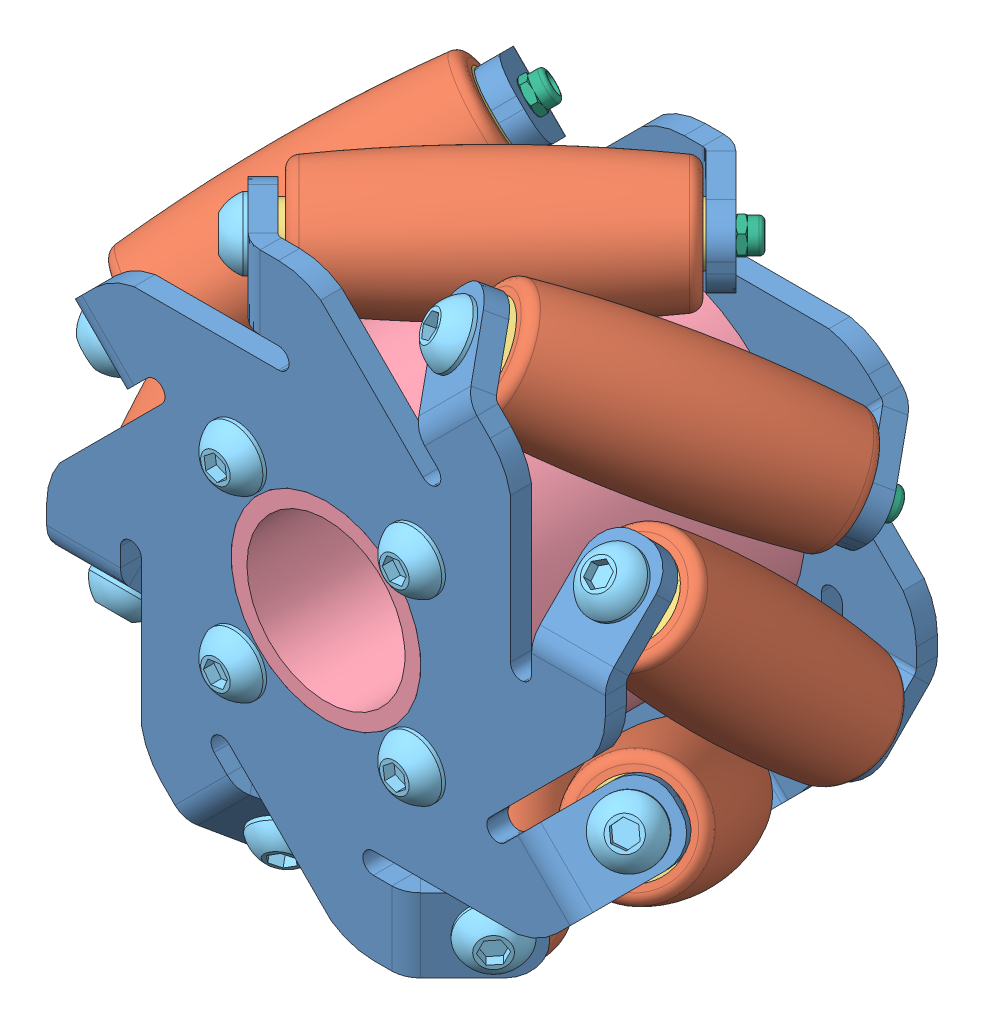
SolidWorks assembly MECANUM WHEEL, configuration Default. Lengths in mm.
Overall size (125.04 125.04 71.6).
51 component instances, 6 part files, 20 mates.
Components (placement in the parent):
- Frame-1: Frame [Default] at (12.3408 21.9505 61.841) x (0 1 0) z (0 0 -1) size (111.31 111.31 16.67)
- Roller-1: Roller [Default] at (12.3982 67.9505 33.7143) x (0.707107 0 -0.707107) z (0.372202 -0.850254 0.372202) size (56 24 24)
- Roller Bracket-1: Roller Bracket [Default] at (30.6779 67.9505 15.4346) x (-0.707107 0 -0.707107) z (0.707107 0 -0.707107) size (15 15 4)
- Shaft-1: Shaft [Default] at (12.3408 21.9505 20.3191) size (64 64 63)
- Frame-2: Frame [Default] at (12.3408 21.9505 6.2972) x (0 1 0) z (0 0 1) size (111.31 111.31 16.67)
- Roller Bracket-2: Roller Bracket [Default] at (-5.8815 67.9505 51.994) x (0.707107 0 0.707107) z (-0.707107 0 0.707107) size (15 15 4)
- Screw-1: Screw [Default] at (7.232 67.9505 38.8805) x (0.707107 0 -0.707107) z (0.582013 0.56791 0.582013) size (71.6 11.4 11.4)
- torque nut 08_iso-2: torque nut 08_iso [ISO 10511-M3-C] at (36.7139 67.9505 9.9933) x (-0.247306 -0.936845 -0.247306) z (0.707107 0 -0.707107) size (5.5 6.35 3.9)
- Roller Bracket-3: Roller Bracket [Default] at (57.834 41.5111 15.4346) x (-0.5 0.5 -0.707107) z (0.5 -0.5 -0.707107) size (15 15 4)
- Roller Bracket-4: Roller Bracket [Default] at (58.3408 3.6134 15.4346) x (0 0.707107 -0.707107) z (0 -0.707107 -0.707107) size (15 15 4)
- Roller Bracket-5: Roller Bracket [Default] at (31.9013 -23.5427 15.4346) x (0.5 0.5 -0.707107) z (-0.5 -0.5 -0.707107) size (15 15 4)
- Roller Bracket-6: Roller Bracket [Default] at (-5.9964 -24.0495 15.4346) x (0.707107 0 -0.707107) z (-0.707107 0 -0.707107) size (15 15 4)
- Roller Bracket-7: Roller Bracket [Default] at (-33.1525 2.3899 15.4346) x (0.5 -0.5 -0.707107) z (-0.5 0.5 -0.707107) size (15 15 4)
- Roller Bracket-8: Roller Bracket [Default] at (-33.6592 40.2876 15.4346) x (0 -0.707107 -0.707107) z (0 0.707107 -0.707107) size (15 15 4)
- Roller Bracket-9: Roller Bracket [Default] at (-7.2198 67.4437 15.4346) x (-0.5 -0.5 -0.707107) z (0.5 0.5 -0.707107) size (15 15 4)
- torque nut 08_iso-3: torque nut 08_iso [ISO 10511-M3-C] at (62.1021 37.243 9.9933) x (-0.837322 -0.487578 -0.247306) z (0.5 -0.5 -0.707107) size (5.5 6.35 3.9)
- torque nut 08_iso-4: torque nut 08_iso [ISO 10511-M3-C] at (58.3408 -2.4226 9.9933) x (-0.936845 0.247306 -0.247306) z (0 -0.707107 -0.707107) size (5.5 6.35 3.9)
- torque nut 08_iso-5: torque nut 08_iso [ISO 10511-M3-C] at (27.6333 -27.8108 9.9933) x (-0.487578 0.837322 -0.247306) z (-0.5 -0.5 -0.707107) size (5.5 6.35 3.9)
- torque nut 08_iso-6: torque nut 08_iso [ISO 10511-M3-C] at (-12.0324 -24.0495 9.9933) x (0.247306 0.936845 -0.247306) z (-0.707107 0 -0.707107) size (5.5 6.35 3.9)
- torque nut 08_iso-7: torque nut 08_iso [ISO 10511-M3-C] at (-37.4206 6.658 9.9933) x (0.837322 0.487578 -0.247306) z (-0.5 0.5 -0.707107) size (5.5 6.35 3.9)
- torque nut 08_iso-8: torque nut 08_iso [ISO 10511-M3-C] at (-33.6592 46.3236 9.9933) x (0.936845 -0.247306 -0.247306) z (0 0.707107 -0.707107) size (5.5 6.35 3.9)
- torque nut 08_iso-9: torque nut 08_iso [ISO 10511-M3-C] at (-2.9518 71.7118 9.9933) x (0.487578 -0.837322 -0.247306) z (0.5 0.5 -0.707107) size (5.5 6.35 3.9)
- Roller-2: Roller [Default] at (44.9083 54.4368 33.7143) x (0.5 -0.5 -0.707107) z (-0.338034 -0.864407 0.372202) size (56 24 24)
- Roller-3: Roller [Default] at (58.3408 21.8931 33.7143) x (0 -0.707107 -0.707107) z (-0.850254 -0.372202 0.372202) size (56 24 24)
- Roller-4: Roller [Default] at (44.8271 -10.617 33.7143) x (-0.5 -0.5 -0.707107) z (-0.864407 0.338034 0.372202) size (56 24 24)
- Roller-5: Roller [Default] at (12.2833 -24.0495 33.7143) x (-0.707107 0 -0.707107) z (-0.372202 0.850254 0.372202) size (56 24 24)
- Roller-6: Roller [Default] at (-20.2268 -10.5358 33.7143) x (-0.5 0.5 -0.707107) z (0.338034 0.864407 0.372202) size (56 24 24)
- Roller-7: Roller [Default] at (-33.6592 22.0079 33.7143) x (0 0.707107 -0.707107) z (0.850254 0.372202 0.372202) size (56 24 24)
- Roller-8: Roller [Default] at (-20.1456 54.518 33.7143) x (0.5 0.5 -0.707107) z (0.864407 -0.338034 0.372202) size (56 24 24)
- Roller Bracket-10: Roller Bracket [Default] at (31.9826 67.3625 51.994) x (0.5 -0.5 0.707107) z (-0.5 0.5 0.707107) size (15 15 4)
- Roller Bracket-11: Roller Bracket [Default] at (58.3408 40.1728 51.994) x (0 -0.707107 0.707107) z (0 0.707107 0.707107) size (15 15 4)
- Roller Bracket-12: Roller Bracket [Default] at (57.7528 2.3087 51.994) x (-0.5 -0.5 0.707107) z (0.5 0.5 0.707107) size (15 15 4)
- Roller Bracket-13: Roller Bracket [Default] at (30.563 -24.0495 51.994) x (-0.707107 0 0.707107) z (0.707107 0 0.707107) size (15 15 4)
- Roller Bracket-14: Roller Bracket [Default] at (-7.3011 -23.4615 51.994) x (-0.5 0.5 0.707107) z (0.5 -0.5 0.707107) size (15 15 4)
- Roller Bracket-15: Roller Bracket [Default] at (-33.6592 3.7282 51.994) x (0 0.707107 0.707107) z (0 -0.707107 0.707107) size (15 15 4)
- Roller Bracket-16: Roller Bracket [Default] at (-33.0713 41.5923 51.994) x (0.5 0.5 0.707107) z (-0.5 -0.5 0.707107) size (15 15 4)
- Screw-2: Screw [Default] at (41.2553 58.0898 38.8805) x (0.5 -0.5 -0.707107) z (0.813118 -0.009973 0.582013) size (71.6 11.4 11.4)
- Screw-3: Screw [Default] at (58.3408 27.0592 38.8805) x (0 -0.707107 -0.707107) z (0.56791 -0.582013 0.582013) size (71.6 11.4 11.4)
- Screw-4: Screw [Default] at (48.4801 -6.964 38.8805) x (-0.5 -0.5 -0.707107) z (-0.009973 -0.813118 0.582013) size (71.6 11.4 11.4)
- Screw-5: Screw [Default] at (17.4495 -24.0495 38.8805) x (-0.707107 0 -0.707107) z (-0.582013 -0.56791 0.582013) size (71.6 11.4 11.4)
- Screw-6: Screw [Default] at (-16.5738 -14.1888 38.8805) x (-0.5 0.5 -0.707107) z (-0.813118 0.009973 0.582013) size (71.6 11.4 11.4)
- Screw-7: Screw [Default] at (-33.6592 16.8418 38.8805) x (0 0.707107 -0.707107) z (-0.56791 0.582013 0.582013) size (71.6 11.4 11.4)
- Screw-8: Screw [Default] at (-23.7986 50.865 38.8805) x (0.5 0.5 -0.707107) z (0.009973 0.813118 0.582013) size (71.6 11.4 11.4)
- Screw-9: Screw [Default] at (-4.6298 38.9211 39.8751) x (0 0 -1) z (0.990301 0.13894 0) size (71.6 11.4 11.4)
- torque nut 08_iso-10: torque nut 08_iso [ISO 10511-M3-N] at (-4.6298 38.9211 1.0191) x (0.923728 0.383049 0) z (0 0 -1) size (5.5 6.35 3.9)
- torque nut 08_iso-12: torque nut 08_iso [ISO 10511-M3-N] at (29.3113 38.9211 1.0191) x (0.383049 -0.923728 0) z (0 0 -1) size (5.5 6.35 3.9)
- torque nut 08_iso-13: torque nut 08_iso [ISO 10511-M3-N] at (29.3113 4.9799 1.0191) x (-0.923728 -0.383049 0) z (0 0 -1) size (5.5 6.35 3.9)
- torque nut 08_iso-14: torque nut 08_iso [ISO 10511-M3-N] at (-4.6298 4.9799 1.0191) x (-0.383049 0.923728 0) z (0 0 -1) size (5.5 6.35 3.9)
- Screw-10: Screw [Default] at (29.3113 38.9211 39.8751) x (0 0 -1) z (0.13894 -0.990301 0) size (71.6 11.4 11.4)
- Screw-11: Screw [Default] at (29.3113 4.9799 39.8751) x (0 0 -1) z (-0.990301 -0.13894 0) size (71.6 11.4 11.4)
- Screw-12: Screw [Default] at (-4.6298 4.9799 39.8751) x (0 0 -1) z (-0.13894 0.990301 0) size (71.6 11.4 11.4)
Mates (geometry in assembly coordinates):
- Concentric2: concentric aligned: cylinder of Shaft-1 through (12.3408 21.9505 2.5691) axis (0 0 1) radius 18; cylinder of Frame-2 through (12.3408 21.9505 2.5691) axis (0 0 1) radius 18
- Concentric3: concentric anti-aligned: cylinder of Frame-1 through (12.3408 21.9505 65.5691) axis (0 0 -1) radius 18; cylinder of Shaft-1 through (12.3408 21.9505 2.5691) axis (0 0 1) radius 18
- Coincident2: coincident anti-aligned: plane of Frame-1 through (49.3408 30.9505 61.5691) normal (0 0 -1); plane of Shaft-1 through (12.3408 21.9505 61.5691) normal (0 0 1)
- Coincident3: coincident anti-aligned: plane of Shaft-1 through (12.3408 21.9505 6.5691) normal (0 0 -1); plane of Frame-2 through (-24.6592 30.9505 6.5691) normal (0 0 1)
- Coincident4: coincident aligned: circle of Frame-1; cylinder of Shaft-1 through (29.3113 38.9211 61.5691) axis (0 0 -1) radius 3
- Coincident5: coincident anti-aligned: cylinder of Shaft-1 through (29.3113 38.9211 61.5691) axis (0 0 -1) radius 3; circle of Frame-2
- Coincident6: coincident aligned: cylinder of Roller Bracket-1 through (32.1972 67.9505 13.9153) axis (-0.707107 0 0.707107) radius 7.5; circle of Roller-1
- Coincident7: coincident anti-aligned: plane of Roller-1 through (30.0758 67.9505 16.0367) normal (0.707107 0 -0.707107); plane of Roller Bracket-1 through (30.0758 67.9505 16.0367) normal (-0.707107 0 0.707107)
- Coincident8: coincident anti-aligned: plane of Roller-1 through (-5.2795 67.9505 51.392) normal (-0.707107 0 0.707107); plane of Roller Bracket-2 through (-5.2795 67.9505 51.392) normal (0.707107 0 -0.707107)
- Concentric5: concentric anti-aligned: cylinder of Roller-1 through (-7.4008 67.9505 53.5133) axis (-0.707107 0 0.707107) radius 7.5; cylinder of Roller Bracket-2 through (-7.4008 67.9505 53.5133) axis (0.707107 0 -0.707107) radius 7.5
- Concentric6: concentric aligned: cylinder of Frame-1 through (-10.9363 67.9505 57.0489) axis (0.707107 0 -0.707107) radius 3; cylinder of Roller Bracket-2 through (-7.4008 67.9505 53.5133) axis (0.707107 0 -0.707107) radius 3
- Coincident10: coincident anti-aligned: plane of Frame-1 through (35.7327 30.9505 98.061) normal (0.707107 0 -0.707107); plane of Roller Bracket-2 through (-8.1079 67.9505 54.2204) normal (-0.707107 0 0.707107)
- Concentric7: concentric aligned: cylinder of Roller-1 through (-7.4008 67.9505 53.5133) axis (-0.707107 0 0.707107) radius 3; cylinder of Screw-1 through (-10.9363 67.9505 57.0489) axis (-0.707107 0 0.707107) radius 2.2
- Coincident11: coincident anti-aligned: plane of Frame-1 through (32.9043 30.9505 100.8895) normal (-0.707107 0 0.707107); plane of Screw-1 through (-10.9363 67.9505 57.0489) normal (0.707107 0 -0.707107)
- Concentric10: concentric anti-aligned: cylinder of Frame-2 through (35.6179 67.9505 11.0893) axis (-0.707107 0 0.707107) radius 3; cylinder of torque nut 08_iso-2 through (50.1843 67.9505 -3.4771) axis (0.707107 0 -0.707107) radius 1.5
- Coincident12: coincident anti-aligned: plane of Frame-2 through (-8.2228 30.9505 -32.7513) normal (0.707107 0 -0.707107); plane of torque nut 08_iso-2 through (33.5143 69.0611 8.9858) normal (-0.707107 0 0.707107)
- Concentric11: concentric anti-aligned: cylinder of Frame-1 through (-4.6298 38.9211 65.5691) axis (0 0 -1) radius 3; cylinder of Screw-9 through (-4.6298 38.9211 65.5691) axis (0 0 1) radius 2.2
- Coincident13: coincident anti-aligned: plane of Frame-1 through (49.3408 30.9505 65.5691) normal (0 0 1); plane of Screw-9 through (-4.6298 38.9211 65.5691) normal (0 0 -1)
- Concentric12: concentric anti-aligned: cylinder of Frame-2 through (-4.6298 38.9211 2.5691) axis (0 0 1) radius 3; cylinder of torque nut 08_iso-10 through (-4.6298 38.9211 -18.0309) axis (0 0 -1) radius 1.5
- Coincident14: coincident anti-aligned: plane of Frame-2 through (-24.6592 30.9505 2.5691) normal (0 0 -1); plane of torque nut 08_iso-10 through (-3.4135 35.9878 2.5691) normal (0 0 1)
